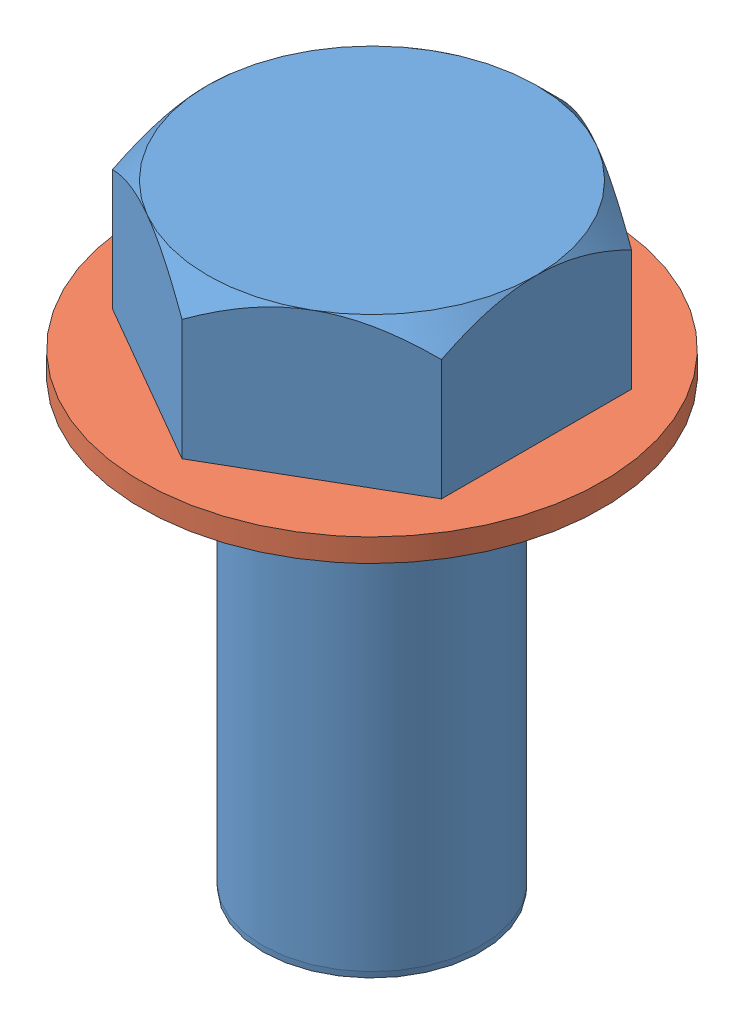
SolidWorks assembly Assem1, configuration Default. Lengths in mm.
Overall size (28.24 26.67 28.24).
2 component instances, 2 part files, 2 mates.
Components (placement in the parent):
- Bolt 3-8 inch-1: Bolt 3-8 inch [Default] at (7.6255 22.0938 20.8917) size (14.3 26.67 18.16)
- Washer-1: Washer [Default] at (7.6255 21.0938 20.8917) x (0.74595 0 -0.666002) z (0.666002 0 0.74595) size (20 1 20)
Mates (geometry in assembly coordinates):
- Concentric1: concentric anti-aligned: cylinder of Bolt 3-8 inch-1 through (7.6255 1.7738 20.8917) axis (0 1 0) radius 4.7625; cylinder of Washer-1 through (7.6255 22.0938 20.8917) axis (0 -1 0) radius 5
- Coincident1: coincident anti-aligned: plane of Bolt 3-8 inch-1 through (7.6255 22.0938 20.8917) normal (0 -1 0); plane of Washer-1 through (7.6255 22.0938 20.8917) normal (0 1 0)
